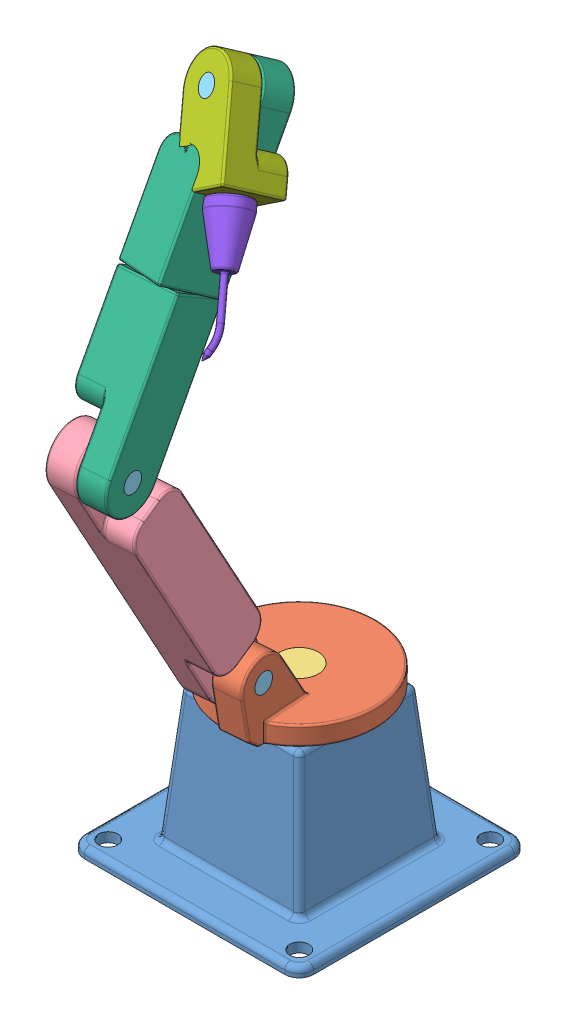
SolidWorks assembly Assem3, configuration Default. Lengths in mm.
Overall size (240 775.53 386.69).
13 component instances, 8 part files, 24 mates.
Components (placement in the parent):
- Base-1: Base [Default] at origin size (240 150 240)
- Link_T-1: Link_T [Default] at (0 150 0) x (0.073377 0 0.997304) z (-0.997304 0 0.073377) size (179.64 80.62 160)
- Pin_Long-1: Pin_Long [Default] at origin size (40 170 40)
- Link_Long-1: Link_Long [Default] at (40.8644 336.357 146.5619) x (0.03628 0.869214 0.493103) z (-0.997304 0 0.073377) size (360 61.62 60)
- Pin_Short-1: Pin_Short [Default] at (-24.4159 205.9749 76.9991) x (0.063546 0.5 0.863691) z (-0.036688 0.866025 -0.498652) size (20 60 20)
- Pin_Short-2: Pin_Short [Default] at (-13.5319 466.7392 224.9299) x (0.063546 0.5 0.863691) z (-0.036688 0.866025 -0.498652) size (20 60 20)
- Pin_Short-3: Pin_Short [Default] at (14.2726 709.2483 43.6061) x (0.880498 0.470804 0.055381) z (0.360027 -0.740134 0.567963) size (20 60 20)
- Pin_Short-4: Pin_Short [Default] at (55.6604 648.8409 131.0017) x (0.589374 0.714773 0.376482) z (-0.663859 0.162948 0.72989) size (20 60 20)
- Pin_Short-5: Pin_Short [Default] at (11.8407 569.5046 160.9339) x (-0.596541 0.394044 0.699191) z (-0.801688 -0.333683 -0.495936) size (20 60 20)
- Link_Half-1: Link_Half [Default] at (-19.2151 595.196 147.6865) x (-0.037888 0.856379 -0.514956) z (0.997304 0 -0.073377) size (180 61.62 60)
- Link_Half-2: Link_Half [Default] at (1.4524 609.6005 170.1208) x (0.037888 -0.856379 0.514956) z (0.308389 -0.480152 -0.821188) size (180 61.62 60)
- Link_End-1: Link_End [Default] at (51.1013 654.8396 89.2497) x (0.460359 -0.680109 0.570545) z (-0.308389 0.480152 0.821188) size (110 61.62 60)
- Tool-1: Tool [Default] at (41.8496 669.2441 113.8854) x (0.887013 0.378284 -0.264782) z (0.035748 -0.627976 -0.777412) size (40 122.85 40)
Mates (geometry in assembly coordinates):
- Concentric1: concentric: cylinder of Base-1 through (0 150 0) axis (0 -1 0) radius 20; cylinder of Link_T-1 through (0 170 0) axis (0 -1 0) radius 20
- Coincident1: coincident: plane of Base-1 through (0 150 0) normal (0 1 0); plane of Link_T-1 through (0 150 0) normal (0 -1 0)
- Concentric2: concentric: cylinder of Link_T-1 through (0 170 0) axis (0 -1 0) radius 20; cylinder of Pin_Long-1 through (0 170 0) axis (0 -1 0) radius 20
- Coincident2: coincident: plane of Link_T-1 through (0 170 0) normal (0 1 0); plane of Pin_Long-1 through (0 170 0) normal (0 1 0)
- Concentric3: concentric: cylinder of Link_T-1 through (49.9519 205.9749 -63.4808) axis (0.5 0 0.866025) radius 10; cylinder of Link_Long-1 through (79.9519 205.9749 -11.5192) axis (-0.5 0 -0.866025) radius 10
- Coincident4: coincident: plane of Link_T-1; plane of Link_Long-1
- Concentric4: concentric: cylinder of Link_Long-1 through (79.9519 205.9749 -11.5192) axis (-0.5 0 -0.866025) radius 10; cylinder of Pin_Short-1 through (49.9519 205.9749 -63.4808) axis (0.5 0 0.866025) radius 10
- Coincident5: coincident: plane of Link_Long-1; plane of Pin_Short-1
- Concentric5: concentric: cylinder of Link_Long-1 through (186.3366 479.6713 -72.9405) axis (-0.5 0 -0.866025) radius 10; cylinder of Link_Half-1 through (156.3366 479.6713 -124.902) axis (0.5 0 0.866025) radius 10
- Coincident7: coincident: plane of Link_Long-1; plane of Link_Half-1
- Concentric6: concentric: cylinder of Link_Long-1 through (186.3366 479.6713 -72.9405) axis (-0.5 0 -0.866025) radius 10; cylinder of Pin_Short-2 through (156.3366 479.6713 -124.902) axis (0.5 0 0.866025) radius 10
- Coincident8: coincident: plane of Link_Long-1; plane of Pin_Short-2
- Concentric7: concentric: cylinder of Pin_Short-5 through (249.0221 635.7267 -143.773) axis (-0.431586 -0.866975 0.249176) radius 10; cylinder of Link_Half-1 through (223.1269 583.7082 -128.8224) axis (0.431586 0.866975 -0.249176) radius 10
- Coincident9: coincident: plane of Pin_Short-5; plane of Link_Half-1
- Concentric8: concentric: cylinder of Pin_Short-5 through (249.0221 635.7267 -143.773) axis (-0.431586 -0.866975 0.249176) radius 10; cylinder of Link_Half-2 through (249.0221 635.7267 -143.773) axis (-0.431586 -0.866975 0.249176) radius 10
- Coincident11: coincident: plane of Pin_Short-5; plane of Link_Half-2
- Concentric9: concentric: cylinder of Link_Half-2 through (326.3543 725.2805 -179.8264) axis (-0.851396 0.482772 0.205076) radius 10; cylinder of Link_End-1 through (275.2705 754.2468 -167.5218) axis (0.851396 -0.482772 -0.205076) radius 10
- Coincident13: coincident: plane of Link_Half-2; plane of Link_End-1
- Concentric10: concentric: cylinder of Pin_Short-3 through (275.2705 754.2468 -167.5218) axis (0.851396 -0.482772 -0.205076) radius 10; cylinder of Link_End-1 through (275.2705 754.2468 -167.5218) axis (0.851396 -0.482772 -0.205076) radius 10
- Coincident14: coincident: plane of Pin_Short-3; plane of Link_End-1
- Concentric11: concentric: cylinder of Pin_Short-4 through (326.0589 772.1881 -145.1914) axis (0.50493 0.64849 0.569654) radius 10; cylinder of Link_End-1 through (326.0589 772.1881 -145.1914) axis (0.50493 0.64849 0.569654) radius 10
- Coincident16: coincident: plane of Pin_Short-4; plane of Link_End-1
- Concentric12: concentric: cylinder of Pin_Short-4 through (326.0589 772.1881 -145.1914) axis (0.50493 0.64849 0.569654) radius 10; cylinder of Tool-1 through (362.4138 818.8794 -104.1763) axis (0.50493 0.64849 0.569654) radius 10
- Coincident17: coincident: plane of Pin_Short-4; plane of Tool-1
